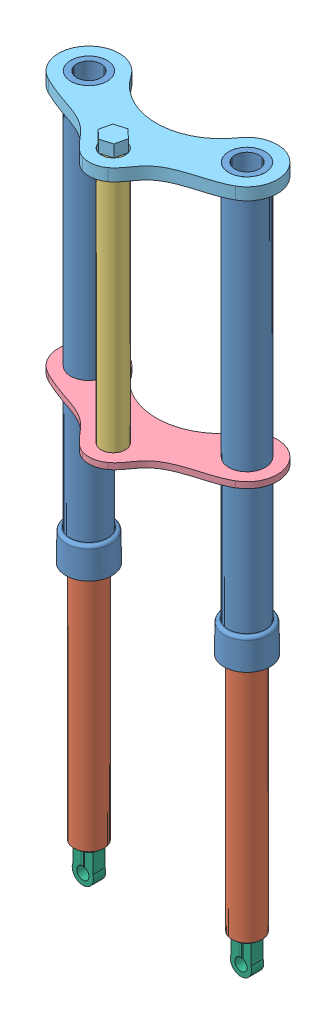
SolidWorks assembly telescopic suspension, configuration Default. Lengths in mm.
Overall size (360 1175.07 180).
7 component instances, 6 part files, 13 mates.
Components (placement in the parent):
- fork rod-1: fork rod [Default] at (731.9541 206.3796 436.0912) size (336 700 76)
- inner fork rod-1: inner fork rod [Default] at (653.5824 -158.3643 436.0912) size (310 530 50)
- single fork-1: single fork [Default] at (776.6274 486.3796 526.0912) size (40 400 40)
- stand fork-1: stand fork [Default] at (776.6219 476.3796 476.128) size (360 10 180)
- stand fork big-1: stand fork big [Default] at (776.6274 886.3796 483.9409) size (360 40 180)
- spnsn part 3-1: spnsn part 3 [Default] at (906.6274 -231.1952 426.0912) size (42 60.33 42)
- spnsn part 3-2: spnsn part 3 [Default] at (646.6274 -231.1952 426.0912) size (42 60.33 42)
Mates (geometry in assembly coordinates):
- Concentric1: concentric aligned: circle of fork rod-1; circle of inner fork rod-1
- Concentric2: concentric aligned: circle of fork rod-1; circle of stand fork-1
- Concentric3: concentric aligned: circle of fork rod-1; circle of stand fork-1
- Concentric4: concentric aligned: circle of fork rod-1; circle of stand fork big-1
- Coincident4: coincident aligned: plane of fork rod-1 through (906.6274 906.3796 436.0912) normal (0 1 0); circle of stand fork big-1
- Coincident5: coincident anti-aligned: cylinder of single fork-1; cylinder of stand fork big-1 through (776.6274 906.3796 526.0912) axis (0 -1 0) radius 20
- Concentric5: concentric aligned: circle of fork rod-1; circle of inner fork rod-1
- Coincident6: coincident aligned: circle of single fork-1; circle of stand fork big-1
- Coincident7: coincident aligned: circle of single fork-1; circle of stand fork-1
- Concentric6: concentric aligned: circle of inner fork rod-1; circle of spnsn part 3-1
- Coincident9: coincident anti-aligned: plane of inner fork rod-1 through (906.6274 -188.3643 436.0912) normal (0 -1 0); circle of spnsn part 3-1
- Concentric7: concentric aligned: circle of inner fork rod-1; circle of spnsn part 3-2
- Coincident11: coincident anti-aligned: plane of inner fork rod-1 through (646.6274 -188.3643 436.0912) normal (0 -1 0); circle of spnsn part 3-2
